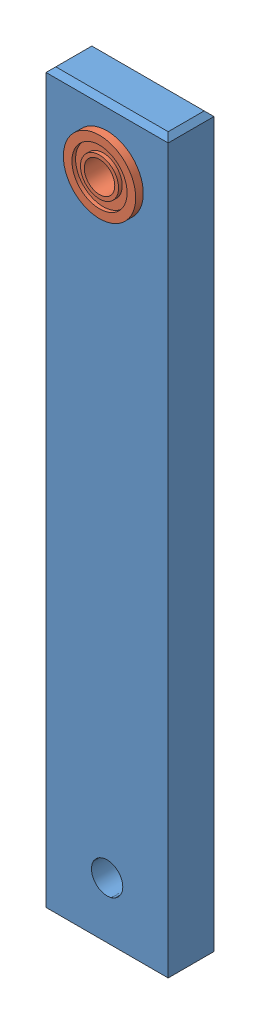
SolidWorks assembly top_link_assy, configuration Default. Lengths in mm.
Overall size (12.7 76.2 6.34).
3 component instances, 2 part files, 17 mates.
Components (placement in the parent):
- top_link-1: top_link [Default] at (0 -6.35 4.7625) x (0 1 0) z (-1 0 0) size (76.2 4.76 12.7)
- FR144-ZZ-3: FR144-ZZ [Default] at (0 -6.35 2.7464) x (-0.97513 -0.221634 0) z (0 0 1) size (7.52 7.52 2.8)
- FR144-ZZ-4: FR144-ZZ [Default] at (0 -6.35 2.0161) x (0.985651 0.168793 0) z (0 0 -1) size (7.52 7.52 2.8)
Mates (geometry in assembly coordinates):
- Parallel1: parallel: plane of top_link-1 through (-6.35 -6.35 0) normal (-1 0 0); plane of ? through (-2.3813 -4.9752 -0.9652) normal (-1 0 0)
- Coincident12: coincident anti-aligned: plane of top_link-1 through (0 -6.35 4.7625) normal (0 0 1); plane of ? through (-0.075 -2.7041 4.7625) normal (0 0 -1)
- Concentric12: concentric: cylinder of top_link-1 through (0 0 0) axis (0 0 -1) radius 1.632; cylinder of ? through (0 0 6.2611) axis (0 0 1) radius 2.7051
- Concentric13: concentric: circle of ?; circle of ?
- Symmetric1: symmetric aligned: plane of top_link-1 through (-6.35 -6.35 0) normal (-1 0 0); plane of top_link-1 through (6.35 -6.35 0) normal (1 0 0); plane of assembly through (0 0 0) normal (1 0 0)
- Coincident34: coincident anti-aligned: plane of top_link-1 through (0 -6.35 0) normal (0 0 -1); plane of assembly through (0 0 0) normal (0 0 1)
- Concentric26: concentric: cylinder of top_link-1 through (0 -6.35 4.7625) axis (0 0 1) radius 1.632; cylinder of ? through (0 -6.35 4.7625) axis (0 0 1) radius 3.2385
- Coincident38: coincident aligned: plane of top_link-1 through (0 -6.35 4.7625) normal (0 0 1); plane of ? through (0 -7.7724 4.7625) normal (0 0 1)
- Concentric27: concentric: cylinder of top_link-1 through (0 -6.35 4.7625) axis (0 0 1) radius 1.632; circle of ?
- Coincident39: coincident: plane of ? through (-2.3813 -4.9752 -0.9652) normal (0 0 1); plane of ? through (0 -6.35 -0.9652) normal (0 0 -1)
- Coincident40: coincident anti-aligned: plane of top_link-1 through (0 -6.35 0) normal (0 0 -1); plane of ? through (0 -6.35 0) normal (0 0 1)
- Coincident41: coincident aligned: plane of top_link-1 through (0 0 0) normal (0 1 0); plane of assembly through (0 0 0) normal (0 1 0)
- Concentric28: concentric: cylinder of top_link-1 through (0 -6.35 4.7625) axis (0 0 1) radius 1.632; cylinder of ? through (0 -6.35 0) axis (0 0 -1) radius 1.5875
- Coincident42: coincident anti-aligned: plane of top_link-1 through (0 -6.35 4.7625) normal (0 0 1); plane of FR144-ZZ-3 through (0 -6.35 4.7625) normal (0 0 -1)
- Concentric29: concentric aligned: cylinder of top_link-1 through (0 -6.35 4.7625) axis (0 0 -1) radius 3.1623; cylinder of FR144-ZZ-3 through (0 -6.35 4.7625) axis (0 0 -1) radius 3.175
- Coincident43: coincident anti-aligned: plane of top_link-1 through (0 -6.35 0) normal (0 0 -1); plane of FR144-ZZ-4 through (0 -6.35 0) normal (0 0 1)
- Concentric30: concentric anti-aligned: cylinder of top_link-1 through (0 -6.35 4.7625) axis (0 0 -1) radius 3.1623; cylinder of FR144-ZZ-4 through (0 -6.35 0) axis (0 0 1) radius 3.175
